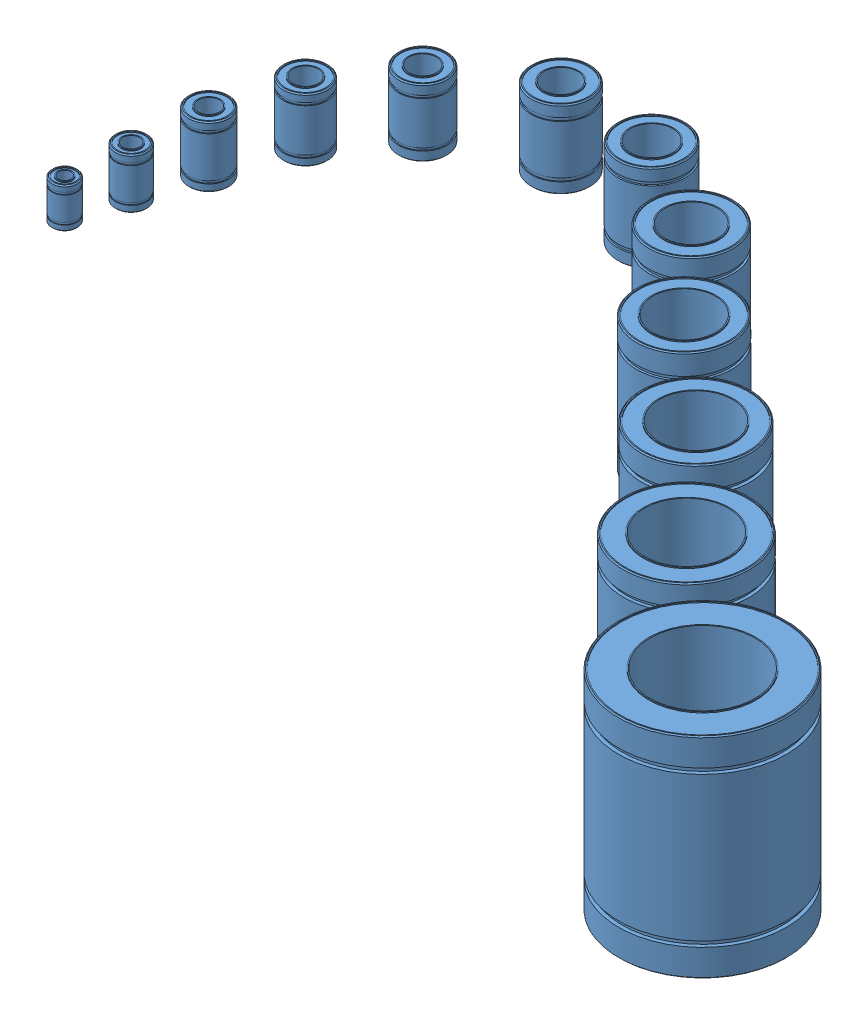
SolidWorks assembly bearings overview, configuration Default. Lengths in mm.
Overall size (401.46 100 262.62).
12 component instances, 1 part files, 12 mates.
Components (placement in the parent):
- Lineare_bearing_LMUU_serie-1: Lineare_bearing_LMUU_serie [LM6UU] at (-93.357 -9.5 107.7174) size (12 19 12)
- Lineare_bearing_LMUU_serie-2: Lineare_bearing_LMUU_serie [LM8UU] at (-91.194 -12 78.1731) size (15 24 15)
- Lineare_bearing_LMUU_serie-3: Lineare_bearing_LMUU_serie [LM10UU] at (-87.6816 -14.5 44.6821) size (19 29 19)
- Lineare_bearing_LMUU_serie-4: Lineare_bearing_LMUU_serie [LM12UU] at (-76.92 -15 9.3336) size (21 30 21)
- Lineare_bearing_LMUU_serie-5: Lineare_bearing_LMUU_serie [LM13UU] at (-53.662 -16 -23.2931) size (23 32 23)
- Lineare_bearing_LMUU_serie-6: Lineare_bearing_LMUU_serie [LM16UU] at (-14.0793 -18.5 -49.5206) size (28 37 28)
- Lineare_bearing_LMUU_serie-7: Lineare_bearing_LMUU_serie [LM20UU] at (32.1966 -21 -46.5262) size (32 42 32)
- Lineare_bearing_LMUU_serie-8: Lineare_bearing_LMUU_serie [LM25UU] at (75.7433 -29.5 -21.8927) size (40 59 40)
- Lineare_bearing_LMUU_serie-9: Lineare_bearing_LMUU_serie [LM30UU] at (111.6261 -32 17.4256) size (45 64 45)
- Lineare_bearing_LMUU_serie-10: Lineare_bearing_LMUU_serie [LM35UU] at (158.3303 -35 58.4887) size (52 70 52)
- Lineare_bearing_LMUU_serie-11: Lineare_bearing_LMUU_serie [LM50UU] at (262.1063 -50 159.0978) size (80 100 80)
- Lineare_bearing_LMUU_serie-12: Lineare_bearing_LMUU_serie [LM40UU] at (202.1944 -40 106.8655) size (60 80 60)
Mates (geometry in assembly coordinates):
- Coincident1: coincident aligned: plane of Lineare_bearing_LMUU_serie-11 through (262.1063 -0.5 159.0978) normal (0 1 0); plane of Lineare_bearing_LMUU_serie-12 through (202.1944 -0.5 106.8655) normal (0 1 0)
- Coincident2: coincident aligned: plane of Lineare_bearing_LMUU_serie-11 through (262.1063 -0.5 159.0978) normal (0 1 0); plane of Lineare_bearing_LMUU_serie-10 through (158.3303 -0.5 58.4887) normal (0 1 0)
- Coincident3: coincident aligned: plane of Lineare_bearing_LMUU_serie-11 through (262.1063 -0.5 159.0978) normal (0 1 0); plane of Lineare_bearing_LMUU_serie-9 through (111.6261 -0.5 17.4256) normal (0 1 0)
- Coincident4: coincident aligned: plane of Lineare_bearing_LMUU_serie-11 through (262.1063 -0.5 159.0978) normal (0 1 0); plane of Lineare_bearing_LMUU_serie-8 through (75.7433 -0.5 -21.8927) normal (0 1 0)
- Coincident5: coincident aligned: plane of Lineare_bearing_LMUU_serie-11 through (262.1063 -0.5 159.0978) normal (0 1 0); plane of Lineare_bearing_LMUU_serie-7 through (32.1966 -0.5 -46.5262) normal (0 1 0)
- Coincident6: coincident aligned: plane of Lineare_bearing_LMUU_serie-11 through (262.1063 -0.5 159.0978) normal (0 1 0); plane of Lineare_bearing_LMUU_serie-6 through (-14.0793 -0.5 -49.5206) normal (0 1 0)
- Coincident7: coincident aligned: plane of Lineare_bearing_LMUU_serie-11 through (262.1063 -0.5 159.0978) normal (0 1 0); plane of Lineare_bearing_LMUU_serie-5 through (-53.662 -0.5 -23.2931) normal (0 1 0)
- Coincident8: coincident aligned: plane of Lineare_bearing_LMUU_serie-11 through (262.1063 -0.5 159.0978) normal (0 1 0); plane of Lineare_bearing_LMUU_serie-4 through (-76.92 -0.5 9.3336) normal (0 1 0)
- Coincident9: coincident aligned: plane of Lineare_bearing_LMUU_serie-11 through (262.1063 -0.5 159.0978) normal (0 1 0); plane of Lineare_bearing_LMUU_serie-3 through (-87.6816 -0.5 44.6821) normal (0 1 0)
- Coincident10: coincident aligned: plane of Lineare_bearing_LMUU_serie-11 through (262.1063 -0.5 159.0978) normal (0 1 0); plane of Lineare_bearing_LMUU_serie-2 through (-91.194 -0.5 78.1731) normal (0 1 0)
- Coincident11: coincident aligned: plane of Lineare_bearing_LMUU_serie-11 through (262.1063 -0.5 159.0978) normal (0 1 0); plane of Lineare_bearing_LMUU_serie-1 through (-93.357 -0.5 107.7174) normal (0 1 0)
- Coincident12: coincident aligned: plane of Lineare_bearing_LMUU_serie-1 through (-90.357 0 107.7174) normal (0 1 0); plane of assembly through (0 0 0) normal (0 1 0)
